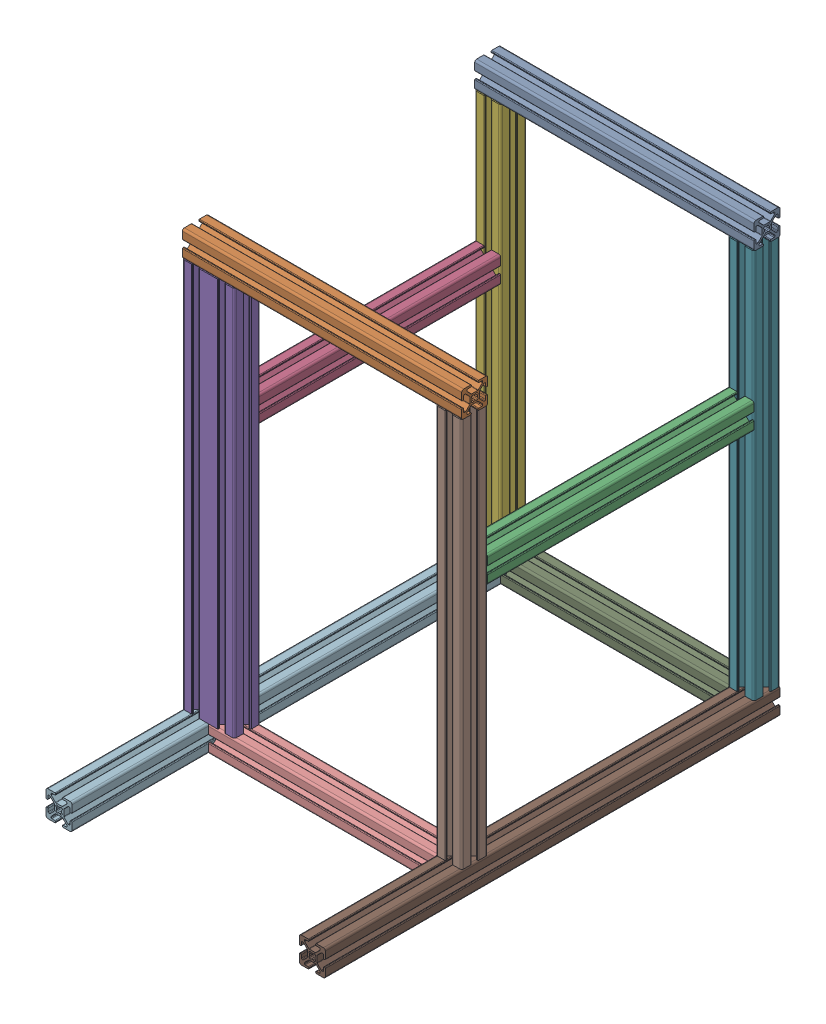
SolidWorks assembly Frame, configuration Default. Lengths in mm.
Overall size (215 340 350).
12 component instances, 6 part files, 0 mates.
Components (placement in the parent):
- 20 series extrusions 20-2020(5)[2]-1: 20 series extrusions 20-2020(5)[2] [Default] at origin size (215 20 20)
- 20 series extrusions 20-2020(5)[2]-2: 20 series extrusions 20-2020(5)[2] [Default] at (0 0 225) size (215 20 20)
- 20 series extrusions 20-2020(5)[4]-1: 20 series extrusions 20-2020(5)[4] [Default] at origin size (20 20 205)
- 20 series extrusions 20-2020(5)[4]-2: 20 series extrusions 20-2020(5)[4] [Default] x (-1 0 0) z (0 0 -1) size (20 20 205)
- Body3-1: Body3 [Default] at origin size (40 300 20)
- 20 series extrusions 20-2020(5)[7]-1: 20 series extrusions 20-2020(5)[7] [Default] at origin size (20 300 20)
- 20 series extrusions 20-2020(5)[7]-2: 20 series extrusions 20-2020(5)[7] [Default] at (195 0 0) size (20 300 20)
- 20 series extrusions 20-2020(5)[7]-3: 20 series extrusions 20-2020(5)[7] [Default] at (195 0 225) size (20 300 20)
- Body5-1: Body5 [Default] at origin size (175 20 20)
- Body5-2: Body5 [Default] at (0 0 225) x (-1 0 0) z (0 0 1) size (175 20 20)
- Body6-1: Body6 [Default] at origin size (20 20 350)
- Body6-2: Body6 [Default] at (-195 0 0) size (20 20 350)
